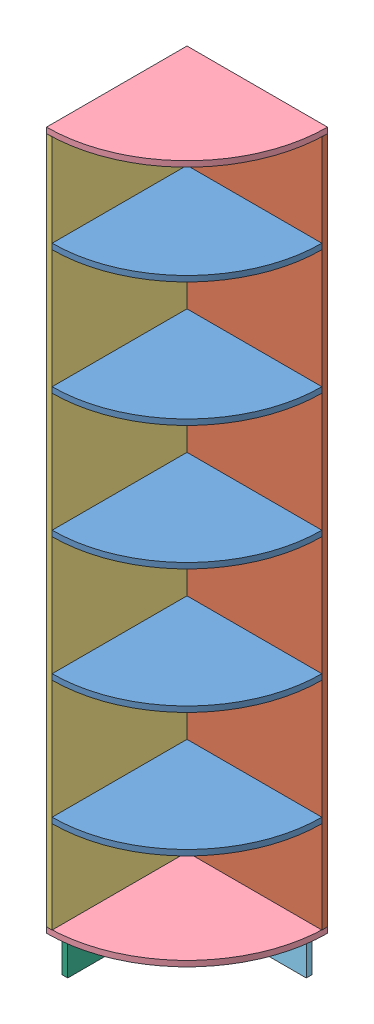
SolidWorks assembly зал угол полка, configuration Default. Lengths in mm.
Overall size (450 2336 450).
11 component instances, 6 part files, 28 mates.
Components (placement in the parent):
- полка-1: полка [Default] at (-468.0758 300.0008 511.8818) size (432 18 432)
- бок2-1: бок2 [Default] at (-468.0758 -1586.9992 493.8818) size (432 2200 18)
- бок1-1: бок1 [Default] at (-486.0758 -1586.9992 943.8818) x (0 0 -1) z (1 0 0) size (450 2200 18)
- полка большая-1: полка большая [Default] at (-486.0758 -1604.9992 493.8818) size (450 18 450)
- полка большая-2: полка большая [Default] at (-486.0758 613.0008 493.8818) size (450 18 450)
- полка-2: полка [Default] at (-468.0758 -97.9992 511.8818) size (432 18 432)
- полка-3: полка [Default] at (-468.0758 -495.9992 511.8818) size (432 18 432)
- полка-4: полка [Default] at (-468.0758 -893.9992 511.8818) size (432 18 432)
- полка-5: полка [Default] at (-468.0758 -1291.9992 511.8818) size (432 18 432)
- ножка 1-1: ножка 1 [Default] at (-428.0758 -1604.9992 551.8818) x (1 0 0) z (0 1 0) size (382 18 100)
- ножка 2-1: ножка 2 [Default] at (-428.0758 -1604.9992 933.8818) x (0 0 -1) z (0 1 0) size (400 18 100)
Mates (geometry in assembly coordinates):
- Coincident3: coincident anti-aligned: plane of бок2-1 through (-468.0758 -1586.9992 511.8818) normal (-1 0 0); plane of бок1-1 through (-468.0758 -1586.9992 943.8818) normal (1 0 0)
- Coincident4: coincident aligned: plane of бок2-1 through (-468.0758 -1586.9992 493.8818) normal (0 0 -1); plane of бок1-1 through (-468.0758 -1586.9992 493.8818) normal (0 0 -1)
- Coincident5: coincident aligned: plane of бок2-1 through (-468.0758 -1586.9992 511.8818) normal (0 -1 0); plane of бок1-1 through (-468.0758 -1586.9992 943.8818) normal (0 -1 0)
- Coincident6: coincident anti-aligned: line of бок1-1 through (-486.0758 -1586.9992 493.8818) axis (0 1 0); line of полка большая-1 through (-486.0758 -1586.9992 493.8818) axis (0 -1 0)
- Coincident7: coincident anti-aligned: line of бок1-1 through (-486.0758 -1586.9992 943.8818) axis (0 0 -1); line of полка большая-1 through (-486.0758 -1586.9992 493.8818) axis (0 0 1)
- Coincident8: coincident anti-aligned: line of бок1-1 through (-486.0758 -1586.9992 493.8818) axis (0 1 0); line of полка большая-2 through (-486.0758 631.0008 493.8818) axis (0 -1 0)
- Coincident9: coincident aligned: line of бок2-1 through (-36.0758 613.0008 493.8818) axis (-1 0 0); line of полка большая-2 through (-36.0758 613.0008 493.8818) axis (-1 0 0)
- Coincident10: coincident aligned: line of полка-1 through (-468.0758 278.0008 511.8818) axis (0 -1 0); line of полка-2 through (-468.0758 -119.9992 511.8818) axis (0 -1 0)
- Coincident11: coincident aligned: line of полка-2 through (-468.0758 -119.9992 511.8818) axis (0 -1 0); line of полка-3 through (-468.0758 -517.9992 511.8818) axis (0 -1 0)
- Coincident12: coincident aligned: line of полка-3 through (-468.0758 -517.9992 511.8818) axis (0 -1 0); line of полка-4 through (-468.0758 -915.9992 511.8818) axis (0 -1 0)
- Coincident13: coincident aligned: line of полка-4 through (-468.0758 -915.9992 511.8818) axis (0 -1 0); line of полка-5 through (-468.0758 -1313.9992 511.8818) axis (0 -1 0)
- Coincident14: coincident aligned: line of бок2-1 through (-468.0758 613.0008 511.8818) axis (0 -1 0); line of полка-5 through (-468.0758 -1313.9992 511.8818) axis (0 -1 0)
- Coincident15: coincident aligned: plane of полка-4 through (-468.0758 -915.9992 511.8818) normal (-1 0 0); plane of полка-5 through (-468.0758 -1313.9992 511.8818) normal (-1 0 0)
- Coincident16: coincident aligned: plane of полка-3 through (-468.0758 -517.9992 511.8818) normal (-1 0 0); plane of полка-4 through (-468.0758 -915.9992 511.8818) normal (-1 0 0)
- Coincident17: coincident aligned: plane of полка-2 through (-468.0758 -119.9992 511.8818) normal (-1 0 0); plane of полка-3 through (-468.0758 -517.9992 511.8818) normal (-1 0 0)
- Coincident18: coincident aligned: plane of полка-1 through (-468.0758 278.0008 511.8818) normal (-1 0 0); plane of полка-2 through (-468.0758 -119.9992 511.8818) normal (-1 0 0)
- Coincident19: coincident anti-aligned: plane of полка-1 through (-468.0758 278.0008 511.8818) normal (-1 0 0); plane of бок1-1 through (-468.0758 -1586.9992 943.8818) normal (1 0 0)
- Coincident20: coincident anti-aligned: plane of полка большая-1 through (-486.0758 -1604.9992 493.8818) normal (0 -1 0); plane of ножка 2-1 through (-446.0758 -1604.9992 933.8818) normal (0 1 0)
- Distance1: distance = 40 mm aligned: plane of полка большая-1 through (-486.0758 -1586.9992 943.8818) normal (-1 0 0); plane of ножка 2-1 through (-446.0758 -1604.9992 933.8818) normal (-1 0 0)
- Coincident22: coincident anti-aligned: plane of полка большая-1 through (-486.0758 -1604.9992 493.8818) normal (0 -1 0); plane of ножка 1-1 through (-428.0758 -1604.9992 533.8818) normal (0 1 0)
- Coincident23: coincident anti-aligned: plane of ножка 1-1 through (-428.0758 -1604.9992 533.8818) normal (-1 0 0); plane of ножка 2-1 through (-428.0758 -1604.9992 933.8818) normal (1 0 0)
- Coincident24: coincident aligned: plane of ножка 1-1 through (-428.0758 -1604.9992 533.8818) normal (0 0 -1); plane of ножка 2-1 through (-446.0758 -1604.9992 533.8818) normal (0 0 -1)
- Distance2: distance = 40 mm aligned: plane of ножка 1-1 through (-428.0758 -1604.9992 533.8818) normal (0 0 -1); plane of полка большая-1 through (-486.0758 -1586.9992 493.8818) normal (0 0 -1)
- Distance3: distance = 380 mm anti-aligned: plane of полка-3 through (-468.0758 -477.9992 511.8818) normal (0 1 0); plane of полка-2 through (-468.0758 -97.9992 511.8818) normal (0 -1 0)
- Distance4: distance = 380 mm anti-aligned: plane of полка-3 through (-468.0758 -495.9992 511.8818) normal (0 -1 0); plane of полка-4 through (-468.0758 -875.9992 511.8818) normal (0 1 0)
- Distance5: distance = 380 mm anti-aligned: plane of полка-5 through (-468.0758 -1273.9992 511.8818) normal (0 1 0); plane of полка-4 through (-468.0758 -893.9992 511.8818) normal (0 -1 0)
- Distance6: distance = 295 mm anti-aligned: plane of полка большая-1 through (-486.0758 -1586.9992 493.8818) normal (0 1 0); plane of полка-5 through (-468.0758 -1291.9992 511.8818) normal (0 -1 0)
- Distance7: distance = 380 mm anti-aligned: plane of полка-2 through (-468.0758 -79.9992 511.8818) normal (0 1 0); plane of полка-1 through (-468.0758 300.0008 511.8818) normal (0 -1 0)
